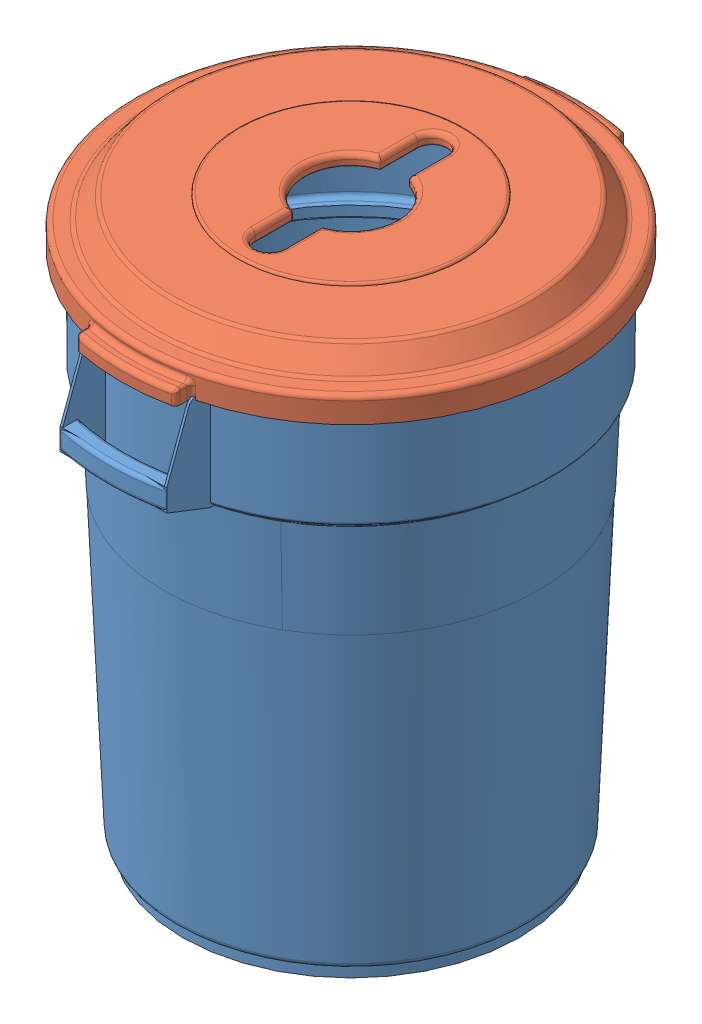
SolidWorks assembly Recycling Bin, configuration Default. Lengths in mm.
Overall size (565.15 736.64 637.88).
2 component instances, 2 part files, 0 mates.
Components (placement in the parent):
- Recycling Bin_Can-1: Recycling Bin_Can [Default] at origin size (558.8 701.68 637.88)
- Recycling Bin_Lid-1: Recycling Bin_Lid [Default] at (0 655.6375 0) size (565.15 65.13 603.25)
